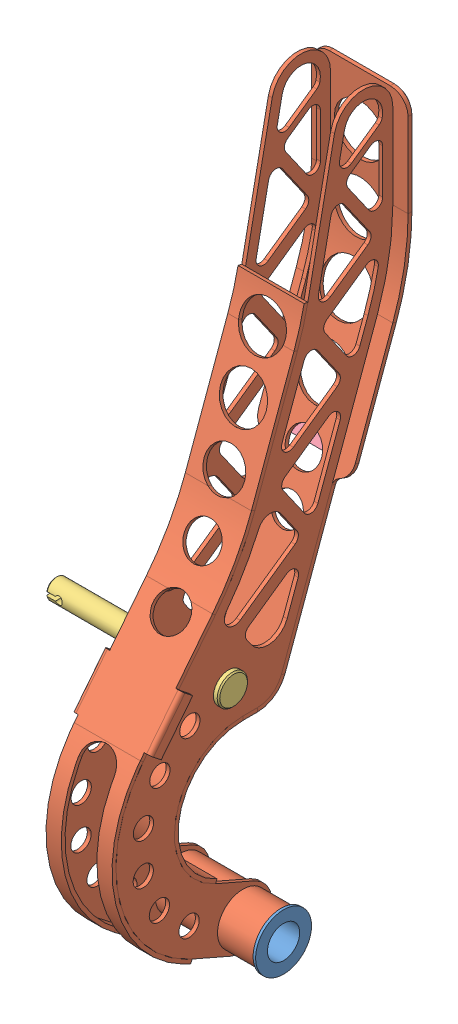
SolidWorks assembly PedalGas, configuration Default. Lengths in mm.
Overall size (84 270.3 131.62).
6 component instances, 5 part files, 10 mates.
Components (placement in the parent):
- PedalBushing-1: PedalBushing [Default] at (0.711 -1.5208 79.5067) x (0 0 -1) z (1 0 0) size (22 22 14)
- PedalBushing-2: PedalBushing [Default] at (43.711 -1.5208 79.5067) x (0 0 1) z (-1 0 0) size (22 22 14)
- PedalGas4-2: PedalGas4 [Default] at (14.711 -80.6117 383.2811) size (47 270.3 131.62)
- PedalGasThrottlePull-1: PedalGasThrottlePull [Default] at (27.711 80.0772 85.1633) x (0 0 1) z (-1 0 0) size (11.94 11.94 70)
- PedalPadBrake-1: PedalPadBrake [Default] at (14.711 -81.2147 382.239) x (0 0.003274 -0.999995) z (1 0 0) size (23.29 116.75 36)
- Basic External Retaining Ring_AI-1: Basic External Retaining Ring_AI [B27.1 - NA1-31] at (1.711 80.0772 85.1633) x (0 0 -1) z (1 0 0) size (9 10.67 0.64)
Mates (geometry in assembly coordinates):
- Concentric1: concentric: cylinder of PedalBushing-2 through (43.711 -1.5208 79.5067) axis (1 0 0) radius 8; cylinder of PedalGas4-2 through (-4.289 -1.5208 79.5067) axis (1 0 0) radius 10
- Coincident1: coincident: plane of PedalBushing-2 through (42.711 9.4792 79.5067) normal (-1 0 0); plane of PedalGas4-2 through (42.711 -1.5208 79.5067) normal (1 0 0)
- Concentric2: concentric: cylinder of PedalBushing-1 through (0.711 -1.5208 79.5067) axis (-1 0 0) radius 8; cylinder of PedalGas4-2 through (-4.289 -1.5208 79.5067) axis (1 0 0) radius 10
- Coincident2: coincident: plane of PedalBushing-1 through (1.711 9.4792 79.5067) normal (1 0 0); plane of PedalGas4-2 through (1.711 245.6792 32.1067) normal (-1 0 0)
- Concentric3: concentric: cylinder of PedalGas4-2 through (-4.289 80.0772 85.1633) axis (1 0 0) radius 4; cylinder of PedalGasThrottlePull-1 through (-72.3961 80.0772 85.1633) axis (-1 0 0) radius 3.9688
- Coincident6: coincident: plane of PedalGasThrottlePull-1 through (27.711 86.046 85.1633) normal (-1 0 0); plane of PedalGas4-2 through (27.711 245.6792 32.1067) normal (1 0 0)
- Concentric13: concentric: cylinder of assembly; cylinder of assembly; cylinder of PedalGas4-2 through (14.711 198.5296 152.3912) axis (0 -0.34202 -0.939693) radius 10; cylinder of PedalPadBrake-1 through (14.711 168.9195 71.0382) axis (0 -0.34202 -0.939693) radius 11
- Coincident17: coincident: plane of PedalGas4-2 through (-4.289 73.546 62.951) normal (0 -0.34202 -0.939693); plane of ? through (-3.289 137.3614 39.7241) normal (0 0.34202 0.939693)
- Concentric14: concentric: cylinder of PedalGasThrottlePull-1 through (-72.3961 80.0772 85.1633) axis (-1 0 0) radius 3.668; cylinder of Basic External Retaining Ring_AI-1 through (1.076 80.0772 85.1633) axis (1 0 0) radius 3.683
- Coincident18: coincident: plane of PedalGasThrottlePull-1 through (1.711 84.046 85.1633) normal (-1 0 0); plane of Basic External Retaining Ring_AI-1 through (1.711 80.0772 85.1633) normal (1 0 0)
